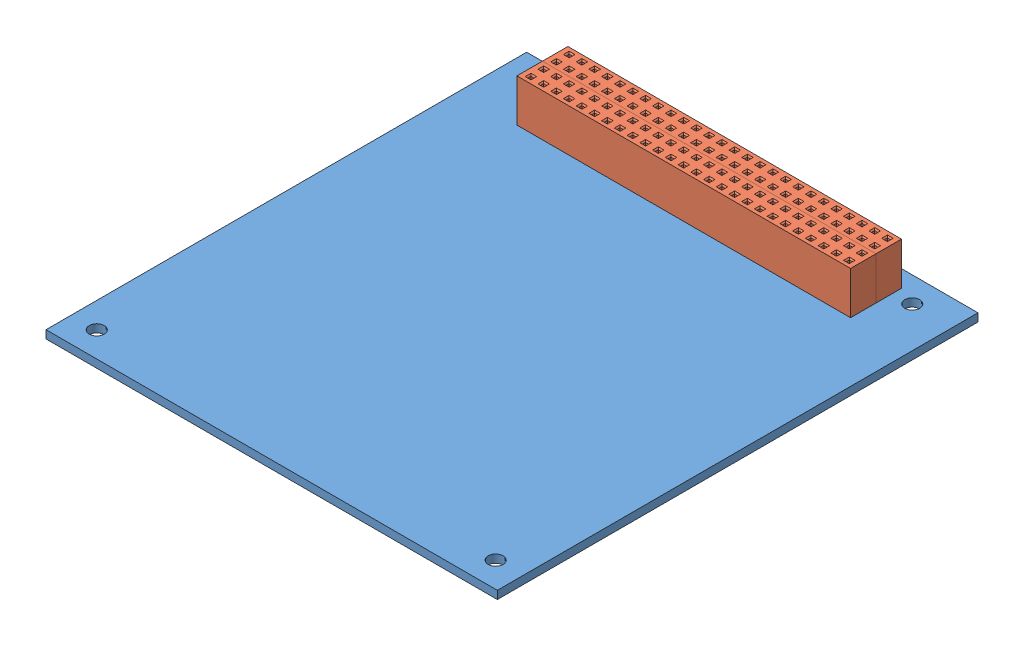
SolidWorks assembly Radio Board, configuration Default. Lengths in mm.
Overall size (90.04 10.11 95.88).
4 component instances, 2 part files, 0 mates.
Components (placement in the parent):
- CBA1-1: CBA1 [Default] at (29.9605 38.2874 84.6534) size (90.04 10.11 95.88)
  - CircuitBoardPart-1: CircuitBoardPart [Default] at (16.1729 24.9915 100.962) size (90.04 1.6 95.88)
  - Connector1-1: Connector1 [Default] at (58.4854 26.5915 13.5645) size (66.55 8.51 5.08)
  - Connector1-2: Connector1 [Default] at (58.4854 26.5915 18.6445) size (66.55 8.51 5.08)
